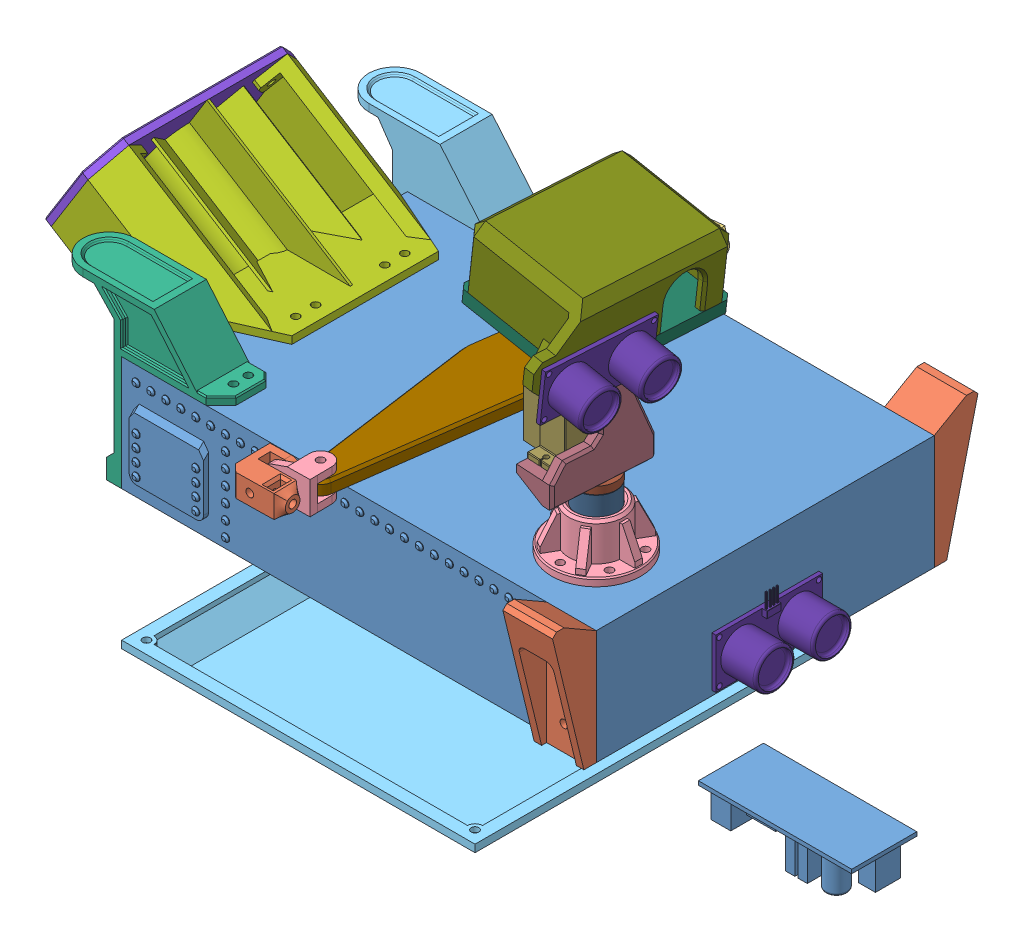
SolidWorks assembly bodySub, configuration Default. Lengths in mm.
Overall size (371.44 225.8 184.74).
29 component instances, 23 part files, 60 mates.
Components (placement in the parent):
- body-2: body [Default] at (-59.6274 45.8698 243.6864) size (191 46 142)
- shoulder-1: shoulder [Default] at (131.3726 45.8698 107.6864) x (-1 0 0) z (0 0 -1) size (20 53.5 17.6)
- shoulder-2: shoulder [Default] at (111.3726 45.8698 243.6864) size (20 53.5 17.6)
- edison-arduino-1: edison-arduino [Default] at (-46.1831 72.8698 116.5567) x (1 0 0) z (0 0 -1) size (127.2 12.67 72)
- mastMount-top-1: mastMount-top [Default] at (103.3726 91.8698 215.6864) size (36 18 36)
- powerShoulder-left-1: powerShoulder-left [Default] at (-59.6274 45.8698 107.6864) x (-1 0 0) z (0 0 -1) size (66.06 69 21)
- powerShoulder-right-1: powerShoulder-right [Default] at (-59.6274 45.8698 201.6864) x (-1 0 0) z (0 0 -1) size (66.06 69 21)
- power-1: power [Default] at (-59.6274 45.8698 243.6864) x (0 0 1) z (-1 0 0) size (84 85.03 90.67)
- powerCap-1: powerCap [Default] at (-121.6992 84.6566 243.6864) x (0 0 1) z (-0.848048 0.529919 0) size (84 51.88 5)
- differentialBar-1: differentialBar [Default] at (-59.5555 91.8698 243.7761) x (0.999999 0 -0.001056) z (0 1 0) size (30 156 5)
- mastTube-1: mastTube [Default] at (103.3726 46.8698 215.6864) x (0.825018 0 -0.565106) z (0.565106 0 0.825018) size (15.88 70 15.88)
- headSub-1: headSub [Default] at (116.9956 124.4877 204.4774) x (0.998229 0 0.059491) z (-0.059491 0 0.998229) size (66.92 104.36 76.5) (flexible)
  - mastServoMount-1: mastServoMount [Default] at (-12.9321 -7.6178 11.9995) size (16 18 16)
  - hxt900Servo-2: hxt900Servo [Default] at (-7.3758 24.7502 6.4435) x (0 0 1) z (1 0 0) size (31.75 29.37 11.11)
  - hxt900Servo-3: hxt900Servo [Default] at (-18.9883 24.7502 24.6995) x (0 -1 0) z (1 0 0) size (31.75 29.37 11.11)
  - headServoMount-1: headServoMount [Default] at (-7.3758 24.7502 6.4435) x (0 0 1) z (1 0 0) size (39.75 35.75 26.73)
  - headMount-1: headMount [Default] at (-18.3656 24.0482 -3.6685) x (-0.11921 -0.992869 0) z (0 0 -1) size (37.5 30 34)
  - headBaseplate-1: headBaseplate [Default] at (-42.8114 51.6029 -21.6685) x (0 0 1) z (-0.992869 0.11921 0) size (60 5 50)
  - headCanopy-1: headCanopy [Default] at (10.4084 75.4284 -21.6685) x (0 0 1) z (-0.11921 -0.992869 0) size (76.5 50 25)
  - usSensor-2: usSensor [Default] at (6.236 40.678 51.8315) x (0 0 -1) z (-0.11921 -0.992869 0) size (43 15.6 26)
- lipo-1: lipo [Default] at (-49.6274 84.8698 152.1552) x (0 0 1) z (0 1 0) size (75.5 19 32.5)
- powerModule-1: powerModule [Default] at (185.2002 72.8698 230.2312) x (1 0 0) z (0 0 -1) size (61.7 14.59 26.2)
- usSensor-1: usSensor [Default] at (131.3726 67.8698 154.1864) x (0 0 1) z (0 1 0) size (43 15.6 26)
- usSensor-2: usSensor [Default] at (-62.6274 43.3198 154.1864) x (0 0 1) z (0 -1 0) size (43 15.6 26)
- rodHinge-diff-right-3: rodHinge-diff-right [Default] at (110.6155 91.8698 257.2295) x (0.999852 0 -0.01719) z (0.01719 0 0.999852) size (21.11 9.1 17.1)
- rodHinge-diff-left-2: rodHinge-diff-left [Default] at (110.4285 91.8698 98.8941) x (0.993405 0 -0.11466) z (0.11466 0 0.993405) size (21.11 9.1 17.1)
- differentialHinge-3: differentialHinge [Default] at (110.3595 90.8698 242.3359) x (-0.999874 0 0.015895) z (0 -1 0) size (18.65 13.57 13)
- differentialHinge-4: differentialHinge [Default] at (110.3019 97.8698 97.7972) x (-0.993255 0 0.115947) z (0 1 0) size (18.65 13.57 13)
- bodyUnderCover-2: bodyUnderCover [Default] at (82.5726 -6.9205 107.6864) x (1 0 0) z (0 -1 0) size (142.2 136 13)
Mates (geometry in assembly coordinates):
- Coincident1: coincident anti-aligned: plane of body-2 through (-59.6274 91.8698 107.6864) normal (0 0 -1); plane of shoulder-1 through (111.3726 45.8698 107.6864) normal (0 0 1)
- Coincident2: coincident: point of body-2; point of shoulder-1
- Parallel1: parallel aligned: plane of body-2 through (131.3726 91.8698 243.6864) normal (1 0 0); plane of shoulder-1 through (131.3726 45.8698 107.6864) normal (1 0 0)
- Coincident3: coincident anti-aligned: plane of body-2 through (-59.6274 91.8698 243.6864) normal (0 0 1); plane of shoulder-2 through (131.3726 45.8698 243.6864) normal (0 0 -1)
- Coincident4: coincident: point of body-2; point of shoulder-2
- Coincident5: coincident aligned: plane of body-2 through (131.3726 91.8698 243.6864) normal (1 0 0); plane of shoulder-2 through (131.3726 45.8698 243.6864) normal (1 0 0)
- Parallel3: parallel anti-aligned: plane of body-2 through (-59.6274 86.8698 243.6864) normal (0 -1 0); plane of edison-arduino-1 through (-46.1831 72.8698 116.5567) normal (0 1 0)
- Concentric1: concentric anti-aligned: circle of body-2; cylinder of mastMount-top-1 through (103.3726 94.8698 215.6864) axis (0 -1 0) radius 8
- Coincident10: coincident anti-aligned: plane of body-2 through (-59.6274 91.8698 243.6864) normal (0 1 0); plane of mastMount-top-1 through (103.3726 91.8698 215.6864) normal (0 -1 0)
- Parallel6: parallel aligned: plane of body-2 through (131.3726 91.8698 243.6864) normal (1 0 0); plane of mastMount-top-1 through (120.3726 97.0127 217.1864) normal (1 0 0)
- Coincident11: coincident anti-aligned: plane of body-2 through (-59.6274 91.8698 243.6864) normal (-1 0 0); plane of powerShoulder-left-1 through (-59.6274 45.8698 107.6864) normal (1 0 0)
- Coincident12: coincident anti-aligned: plane of body-2 through (-59.6274 91.8698 243.6864) normal (0 1 0); plane of powerShoulder-left-1 through (-59.6274 91.8698 178.2465) normal (0 -1 0)
- Coincident13: coincident: point of body-2; point of powerShoulder-left-1
- Coincident14: coincident anti-aligned: plane of body-2 through (-59.6274 91.8698 243.6864) normal (-1 0 0); plane of powerShoulder-right-1 through (-59.6274 45.8698 243.6864) normal (1 0 0)
- Coincident15: coincident anti-aligned: plane of body-2 through (-59.6274 91.8698 243.6864) normal (0 1 0); plane of powerShoulder-right-1 through (-59.6274 91.8698 173.1262) normal (0 -1 0)
- Coincident16: coincident: point of body-2; point of powerShoulder-right-1
- InPlace1: in place: plane of body-2 through (-59.6274 91.8698 243.6864) normal (-1 0 0); plane of ? through (-59.6274 0 0) normal (-1 0 0); moOrthogonalPlaneRef_w of body-2 through (-59.6274 91.8698 243.6864) normal (-1 0 0); line of ? through (-55 -59.6274 0) axis (0 0 1); plane of body-2 through (-59.6274 91.8698 243.6864) normal (-1 0 0); plane of ? through (-59.6274 0 0) normal (0 0 1); plane of body-2 through (-59.6274 91.8698 243.6864) normal (-1 0 0); unknown of power-1
- Coincident17: coincident aligned: plane of body-2; plane of power-1
- Coincident18: coincident aligned: moOrthogonalPlaneRef_w of body-2 through (-59.6274 45.8698 243.6864) normal (0 1 0); plane of power-1
- Coincident19: coincident anti-aligned: moOrthogonalPlaneRef_w of body-2 through (-59.6274 45.8698 243.6864) normal (0 0 -1); plane of power-1 through (-59.6274 45.8698 243.6864) normal (0 0 1)
- InPlace2: in place: plane of power-1 through (-121.6992 84.6566 243.6864) normal (-0.848048 0.529919 0); plane of ? through (-125.5688 78.4641 0) normal (-0.848048 0.529919 0); plane of power-1 through (-121.6992 84.6566 243.6864) normal (-0.848048 0.529919 0); line of ? through (-55 -125.5688 78.4641) axis (0 0.529919 0.848048); plane of power-1 through (-121.6992 84.6566 243.6864) normal (-0.848048 0.529919 0); unknown of ?; plane of power-1 through (-121.6992 84.6566 243.6864) normal (-0.848048 0.529919 0); unknown of powerCap-1
- Coincident20: coincident aligned: plane of power-1; plane of powerCap-1
- Coincident21: coincident aligned: moOrthogonalPlaneRef_w of power-1 through (-121.6992 84.6566 243.6864) normal (0.529919 0.848048 0); plane of powerCap-1
- Coincident22: coincident anti-aligned: moOrthogonalPlaneRef_w of power-1 through (-121.6992 84.6566 243.6864) normal (0 0 -1); plane of powerCap-1
- Concentric2: concentric aligned: cylinder of mastMount-top-1 through (103.3726 94.8698 215.6864) axis (0 -1 0) radius 8; cylinder of mastTube-1 through (103.3726 116.8698 215.6864) axis (0 -1 0) radius 7.94
- Concentric3: concentric aligned: cylinder of mastTube-1 through (103.3726 116.8698 215.6864) axis (0 -1 0) radius 7.94; line of headSub-1/mastServoMount-1 through (103.3726 130.7684 215.6864) axis (0 -1 0)
- Coincident23: coincident anti-aligned: plane of mastTube-1 through (103.3726 116.8698 215.6864) normal (0 1 0); plane of headSub-1/mastServoMount-1 through (103.3726 116.8698 215.6864) normal (0 -1 0)
- Coincident26: coincident aligned: plane of body-2 through (-59.6274 46.8698 243.6864) normal (0 -1 0); plane of mastTube-1 through (103.3726 46.8698 215.6864) normal (0 -1 0)
- Distance1: distance = 5 mm anti-aligned: plane of edison-arduino-1; plane of body-2 through (126.3726 312.4078 238.6864) normal (-1 0 0)
- Distance2: distance = 5 mm anti-aligned: plane of edison-arduino-1; plane of body-2 through (-54.6274 312.4078 112.6864) normal (0 0 1)
- Coincident38: coincident anti-aligned: plane of body-2 through (-59.6274 72.8698 243.6864) normal (0 -1 0); plane of edison-arduino-1 through (121.3726 72.8698 189.6864) normal (0 1 0)
- Parallel7: parallel anti-aligned: plane of lipo-1 through (-49.6274 84.8698 152.1552) normal (-1 0 0); plane of body-2 through (-54.6274 312.4078 238.6864) normal (1 0 0)
- Distance3: distance = 2 mm anti-aligned: plane of lipo-1 through (-30.6274 84.8698 152.1552) normal (0 1 0); plane of body-2 through (-59.6274 86.8698 243.6864) normal (0 -1 0)
- Distance4: distance = 5 mm anti-aligned: plane of lipo-1 through (-49.6274 84.8698 152.1552) normal (-1 0 0); plane of body-2 through (-54.6274 312.4078 238.6864) normal (1 0 0)
- Distance5: distance = 14 mm anti-aligned: plane of powerModule-1 through (185.2002 72.8698 230.2312) normal (0 1 0); plane of body-2 through (-59.6274 86.8698 243.6864) normal (0 -1 0)
- Parallel10: parallel anti-aligned: plane of body-2 through (-54.6274 312.4078 238.6864) normal (1 0 0); plane of powerModule-1 through (185.2002 71.2798 230.2312) normal (-1 0 0)
- Distance6: distance = 5 mm anti-aligned: plane of powerModule-1 through (-17.1226 71.2798 195.399) normal (0 0 -1); plane of edison-arduino-1
- Coincident46: coincident aligned: plane of edison-arduino-1; plane of powerModule-1 through (-17.1226 71.2798 195.399) normal (-1 0 0)
- Coincident53: coincident anti-aligned: plane of body-2 through (131.3726 91.8698 243.6864) normal (1 0 0); plane of usSensor-1 through (131.3726 67.8698 154.1864) normal (-1 0 0)
- Parallel11: parallel aligned: plane of body-2 through (-59.6274 45.8698 243.6864) normal (0 -1 0); plane of usSensor-1 through (132.9726 47.8698 154.1864) normal (0 -1 0)
- Coincident56: coincident anti-aligned: plane of power-1 through (-62.6274 45.8698 243.6864) normal (-1 0 0); plane of usSensor-2 through (-62.6274 43.3198 154.1864) normal (1 0 0)
- Parallel12: parallel aligned: plane of power-1 through (-62.6274 45.8698 133.6864) normal (0 -1 0); plane of usSensor-2 through (-64.2274 43.3198 154.1864) normal (0 -1 0)
- Coincident61: coincident: point of body-2; point of differentialBar-1
- Parallel18: parallel anti-aligned: plane of body-2 through (-59.6274 91.8698 243.6864) normal (0 1 0); plane of differentialBar-1 through (-59.5555 91.8698 243.7761) normal (0 -1 0)
- Concentric11: concentric anti-aligned: cylinder of differentialBar-1 through (25.4497 91.8688 248.6863) axis (0 1 0) radius 1.55; cylinder of differentialHinge-3 through (25.4497 100.8698 248.6863) axis (0 -1 0) radius 1.55
- Concentric13: concentric anti-aligned: cylinder of differentialBar-1 through (25.2955 91.8688 102.6864) axis (0 1 0) radius 1.55; cylinder of differentialHinge-4 through (25.2955 100.8698 102.6864) axis (0 -1 0) radius 1.55
- Concentric16: concentric anti-aligned: circle of body-2; circle of bodyUnderCover-2
- Concentric15: concentric anti-aligned: circle of body-2; circle of bodyUnderCover-2
- Coincident72: coincident: plane of power-1 through (-59.6274 45.8698 175.6864) normal (0 0 1); line of usSensor-2 through (-64.2274 61.8198 175.6864) axis (0 -1 0)
- Tangent1: tangent anti-aligned: plane of power-1 through (-62.6274 45.8698 133.6864) normal (0 -1 0); cylinder of usSensor-2 through (-62.6264 44.8198 195.6864) axis (-1 0 0) radius 1.05
- Coincident73: coincident: plane of body-2 through (-59.6274 45.8698 175.6864) normal (0 0 1); line of usSensor-1 through (132.9726 49.3698 175.6864) axis (0 1 0)
- Distance7: distance = 2 mm aligned: plane of usSensor-1 through (132.9726 47.8698 154.1864) normal (0 -1 0); plane of body-2 through (-59.6274 45.8698 243.6864) normal (0 -1 0)
- Distance8: distance = 1 mm anti-aligned: plane of differentialBar-1 through (-59.5555 96.8698 243.7761) normal (0 1 0); plane of differentialHinge-3 through (25.4497 97.8698 248.6863) normal (0 -1 0)
- Distance9: distance = 1 mm anti-aligned: plane of differentialBar-1 through (-59.5555 96.8698 243.7761) normal (0 1 0); plane of differentialHinge-4 through (110.3019 97.8698 97.7972) normal (0 -1 0)
- Concentric17: concentric anti-aligned: cylinder of rodHinge-diff-right-3 through (15.9278 94.3698 250.8562) axis (0.01719 0 0.999852) radius 1.55; cylinder of differentialHinge-3 through (16.0481 94.3698 257.8552) axis (-0.01719 0 -0.999852) radius 1.55
- Distance10: distance = 1 mm anti-aligned: plane of rodHinge-diff-right-3 through (110.5296 91.8698 252.2302) normal (0.01719 0 0.999852); plane of differentialHinge-3 through (110.5468 90.8698 253.2301) normal (-0.01719 0 -0.999852)
- Concentric18: concentric anti-aligned: cylinder of rodHinge-diff-left-2 through (15.5707 94.3698 101.7896) axis (-0.11466 0 -0.993405) radius 1.55; cylinder of differentialHinge-4 through (14.7681 94.3698 94.8358) axis (0.11466 0 0.993405) radius 1.55
- Distance11: distance = 1 mm anti-aligned: plane of rodHinge-diff-left-2 through (109.1673 91.8698 87.9667) normal (-0.11466 0 -0.993405); plane of differentialHinge-4 through (109.0526 97.8698 86.9733) normal (0.11466 0 0.993405)
- Distance12: distance = 14 mm anti-aligned: plane of edison-arduino-1 through (-46.1831 72.8698 116.5567) normal (0 1 0); plane of body-2 through (-59.6274 86.8698 243.6864) normal (0 -1 0)
- Parallel19: parallel anti-aligned: plane of body-2 through (126.3726 312.4078 238.6864) normal (-1 0 0); plane of edison-arduino-1 through (76.0169 71.2498 116.5567) normal (1 0 0)
